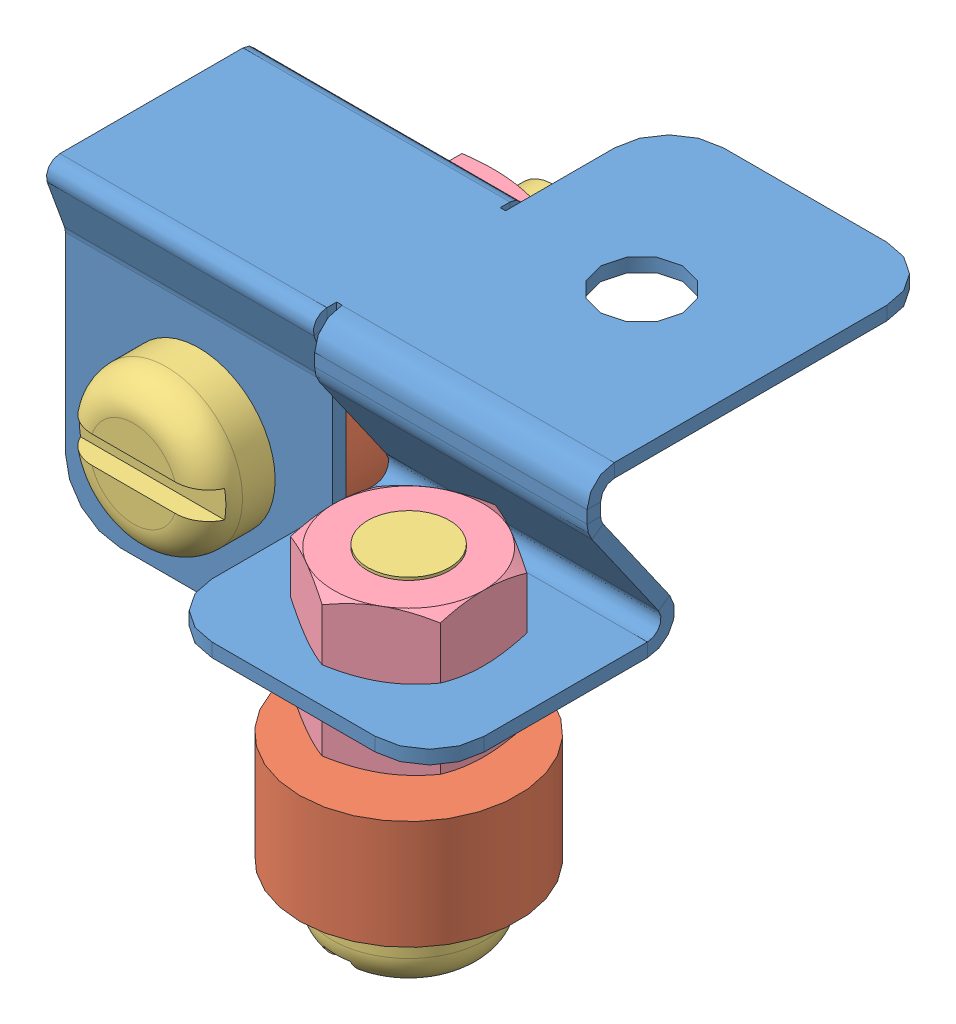
SolidWorks assembly table_support_left_assembly, configuration По умолчанию. Lengths in mm.
Overall size (20 16.29 19.63).
9 component instances, 4 part files, 16 mates.
Components (placement in the parent):
- table_support_1-1: table_support_1 [По умолчанию] at (10.1899 17.102 12.7691) x (1 0 0) z (0 0 -1) size (20 11.63 18.79)
- short_roller-1: short_roller [По умолчанию] at (15.1899 3.2889 18.3288) size (8 4 8)
- short_roller-2: short_roller [По умолчанию] at (5.0899 10.4745 10.8086) x (0 1 0) z (1 0 0) size (8 4 8)
- pan slot head_am-6: pan slot head_am [B18.6.7M - M3 x 0.5 x 10 Slotted PHMS --10N] at (15.1899 0.8889 18.3288) x (0 1 0) z (0 0 1) size (12.48 5.6 5.6)
- pan slot head_am-7: pan slot head_am [B18.6.7M - M3 x 0.5 x 13 Slotted PHMS --13N] at (5.0899 10.4745 18.3295) x (0 0 -1) z (1 0 0) size (15.48 5.6 5.6)
- hex nut style 1_am-2: hex nut style 1_am [B18.2.4.1M - Hex nut, Style 1,  M3 x 0.5 --D-N] at (15.1899 13.1889 18.3288) x (1 0 0) z (0 1 0) size (5.5 6.35 2.4)
- hex nut style 1_am-3: hex nut style 1_am [B18.2.4.1M - Hex nut, Style 1,  M3 x 0.5 --D-N] at (15.1899 7.8889 18.3288) x (1 0 0) z (0 -1 0) size (5.5 6.35 2.4)
- hex nut style 1_am-5: hex nut style 1_am [B18.2.4.1M - Hex nut, Style 1,  M3 x 0.5 --D-N] at (5.0899 10.4745 7.2086) x (0.923728 0.383049 0) z (0 0 -1) size (5.5 6.35 2.4)
- hex nut style 1_am-6: hex nut style 1_am [B18.2.4.1M - Hex nut, Style 1,  M3 x 0.5 --D-N] at (5.0899 10.4745 4.8086) x (0.923728 0.383049 0) z (0 0 -1) size (5.5 6.35 2.4)
Mates (geometry in assembly coordinates):
- Концентричный2: concentric anti-aligned: cylinder of table_support_1-1 through (5.0899 10.4745 5.9295) axis (0 0 1) radius 1.5; cylinder of short_roller-2 through (5.0899 10.4745 14.8086) axis (0 0 -1) radius 1.75
- Расстояние2: distance = 0.7 mm anti-aligned: plane of short_roller-2 through (5.0899 10.4745 10.8086) normal (0 0 -1); plane of table_support_1-1 through (10.1899 20.4745 10.1086) normal (0 0 1)
- Концентричный6: concentric anti-aligned: cylinder of table_support_1-1 through (15.1899 5.944 18.3288) axis (0 1 0) radius 1.5; cylinder of short_roller-1 through (15.1899 7.2889 18.3288) axis (0 -1 0) radius 1.75
- Расстояние3: distance = 3 mm anti-aligned: plane of short_roller-1 through (15.1899 7.2889 18.3288) normal (0 1 0); plane of table_support_1-1 through (10.1899 10.2889 3.5565) normal (0 -1 0)
- Концентричный11: concentric aligned: cylinder of short_roller-1 through (15.1899 7.2889 18.3288) axis (0 -1 0) radius 4; cylinder of pan slot head_am-6 through (15.1899 -24.5111 18.3288) axis (0 -1 0) radius 2.8
- Совпадение8: coincident anti-aligned: plane of short_roller-1 through (15.1899 3.2889 18.3288) normal (0 -1 0); plane of pan slot head_am-6 through (13.6899 3.2889 18.3288) normal (0 1 0)
- Концентричный12: concentric aligned: cylinder of table_support_1-1 through (5.0899 10.4745 5.9295) axis (0 0 1) radius 1.5; cylinder of pan slot head_am-7 through (5.0899 10.4745 43.7295) axis (0 0 1) radius 2.8
- Совпадение9: coincident anti-aligned: plane of table_support_1-1 through (10.1899 20.4745 15.9295) normal (0 0 1); plane of pan slot head_am-7 through (5.0899 11.9745 15.9295) normal (0 0 -1)
- Концентричный13: concentric aligned: cylinder of table_support_1-1 through (15.1899 5.944 18.3288) axis (0 1 0) radius 1.5; cylinder of hex nut style 1_am-2 through (15.1899 -11.8486 18.3288) axis (0 1 0) radius 1.5
- Совпадение10: coincident anti-aligned: plane of table_support_1-1 through (10.1899 10.7889 3.5565) normal (0 1 0); plane of hex nut style 1_am-2 through (15.1899 10.7889 15.1534) normal (0 -1 0)
- Концентричный14: concentric anti-aligned: cylinder of table_support_1-1 through (15.1899 5.944 18.3288) axis (0 1 0) radius 1.5; cylinder of hex nut style 1_am-3 through (15.1899 32.9264 18.3288) axis (0 -1 0) radius 1.5
- Совпадение11: coincident anti-aligned: plane of table_support_1-1 through (10.1899 10.2889 3.5565) normal (0 -1 0); plane of hex nut style 1_am-3 through (15.1899 10.2889 21.5042) normal (0 1 0)
- Концентричный15: concentric anti-aligned: cylinder of table_support_1-1 through (5.0899 10.4745 5.9295) axis (0 0 1) radius 1.5; cylinder of hex nut style 1_am-5 through (5.0899 10.4745 32.2461) axis (0 0 -1) radius 1.5
- Совпадение13: coincident anti-aligned: plane of table_support_1-1 through (10.1899 20.4745 9.6086) normal (0 0 -1); plane of hex nut style 1_am-5 through (6.3062 7.5413 9.6086) normal (0 0 1)
- Концентричный16: concentric anti-aligned: cone of hex nut style 1_am-5 through (5.0899 10.4745 7.4012) axis (0 0 1); cylinder of hex nut style 1_am-6 through (5.0899 10.4745 29.8461) axis (0 0 -1) radius 1.5
- Совпадение14: coincident anti-aligned: plane of hex nut style 1_am-5 through (6.3062 7.5413 7.2086) normal (0 0 -1); plane of hex nut style 1_am-6 through (6.3062 7.5413 7.2086) normal (0 0 1)
